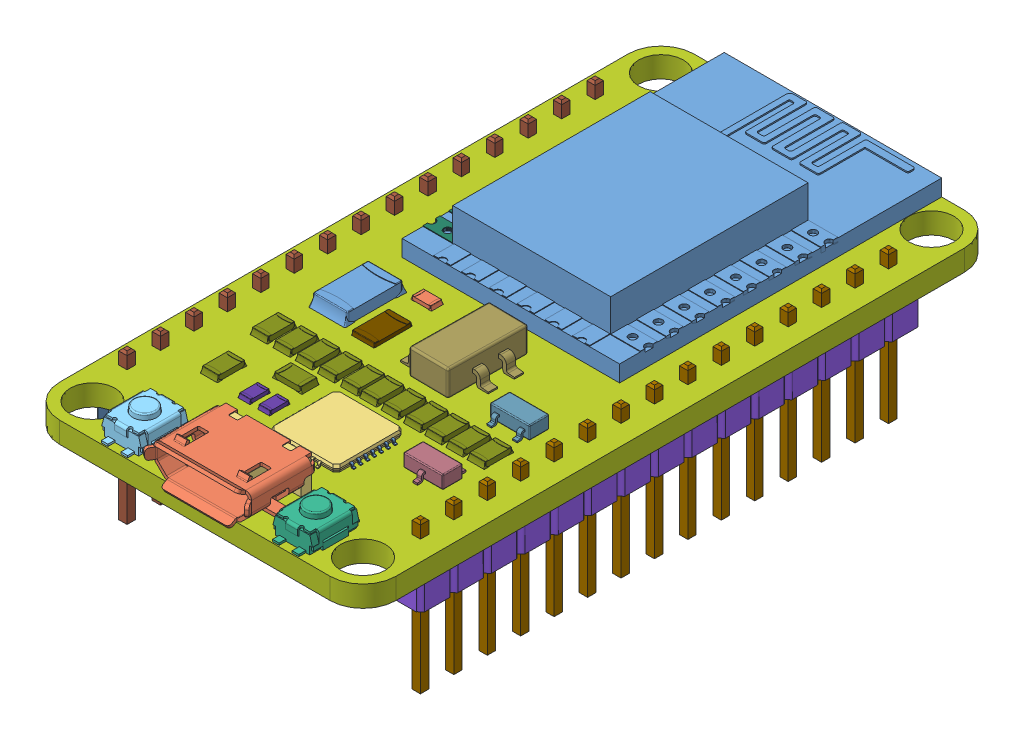
SolidWorks assembly ESP8266 v7, configuration Default. Lengths in mm.
Overall size (25.55 14.09 48.82).
128 component instances, 21 part files, 0 mates.
Components (placement in the parent):
- ESP8266 v7-1: ESP8266 v7 [Default] at origin size (16.52 3.75 40.51)
- micro usb v1-1: micro usb v1 [Default] at (12.6689 12.0548 1.95) x (0 -1 0) z (-1 0 0) size (3.25 6.18 8.01)
  - micro usb shell-1: micro usb shell [Default] at (10.11 -1.95 -0.7124) x (0 0 -1) z (0 1 0) size (8.01 2.95 5.63)
  - micro usb internal-1: micro usb internal [Default] at (10.36 -1.95 -0.7124) x (0 0 -1) z (0 1 0) size (6.9 2.9 4)
  - micro usb contact-1: micro usb contact [Default] at (10.36 -2.05 -2.0124) x (0 0 -1) z (0 1 0) size (0.2 1.3 4.65)
  - micro usb contact-2: micro usb contact [Default] at (10.36 -2.05 -1.3624) x (0 0 -1) z (0 1 0) size (0.2 1.3 4.65)
  - micro usb contact-3: micro usb contact [Default] at (10.36 -2.05 -0.7124) x (0 0 -1) z (0 1 0) size (0.2 1.3 4.65)
  - micro usb contact-4: micro usb contact [Default] at (10.36 -2.05 -0.0624) x (0 0 -1) z (0 1 0) size (0.2 1.3 4.65)
  - micro usb contact-5: micro usb contact [Default] at (10.36 -2.05 0.5876) x (0 0 -1) z (0 1 0) size (0.2 1.3 4.65)
- switch v1-1: switch v1 [Default] at (-4.6798 0 12.1544) x (1 0 0) z (0 1 0) size (3 4.6 1.85)
- switch v1 (1)-1: switch v1 (1) [Default] at (8.3273 0 12.1544) x (1 0 0) z (0 1 0) size (3 4.6 1.85)
- Placa Base-1: Placa Base [Default] at origin size (25.55 11.43 48.19)
  - Placa Base-1: Placa Base [Default] at origin size (25.55 1.6 48.19)
  - Pin Header 1x15 TH Pitch 2.54mm v3 v1-1: Pin Header 1x15 TH Pitch 2.54mm v3 v1 [Default] at (24.996 0.1484 -10.5049) x (0 0 -1) z (0 1 0) size (38.1 2.59 11.43)
    - asm_pin-1: asm_pin [Default] at (-4.318 1.27 0.0014) x (1 0 0) z (0 0 -1) size (2.54 2.59 11.43)
      - spacer-1: spacer [Default] at origin size (2.54 2.59 2.54)
      - pin-1: pin [Default] at origin size (0.64 0.64 11.43)
    - asm_pin_1-1: asm_pin_1 [Default] at (-1.778 1.27 0.0014) x (1 0 0) z (0 0 -1) size (2.54 2.59 11.43)
      - spacer-1: spacer [Default] at origin size (2.54 2.59 2.54)
      - pin-1: pin [Default] at origin size (0.64 0.64 11.43)
    - asm_pin_2-1: asm_pin_2 [Default] at (0.762 1.27 0.0014) x (1 0 0) z (0 0 -1) size (2.54 2.59 11.43)
      - spacer-1: spacer [Default] at origin size (2.54 2.59 2.54)
      - pin-1: pin [Default] at origin size (0.64 0.64 11.43)
    - asm_pin_3-1: asm_pin_3 [Default] at (3.302 1.27 0.0014) x (1 0 0) z (0 0 -1) size (2.54 2.59 11.43)
      - spacer-1: spacer [Default] at origin size (2.54 2.59 2.54)
      - pin-1: pin [Default] at origin size (0.64 0.64 11.43)
    - asm_pin_4-1: asm_pin_4 [Default] at (5.842 1.27 0.0014) x (1 0 0) z (0 0 -1) size (2.54 2.59 11.43)
      - spacer-1: spacer [Default] at origin size (2.54 2.59 2.54)
      - pin-1: pin [Default] at origin size (0.64 0.64 11.43)
    - asm_pin_5-1: asm_pin_5 [Default] at (8.382 1.27 0.0014) x (1 0 0) z (0 0 -1) size (2.54 2.59 11.43)
      - spacer-1: spacer [Default] at origin size (2.54 2.59 2.54)
      - pin-1: pin [Default] at origin size (0.64 0.64 11.43)
    - asm_pin_6-1: asm_pin_6 [Default] at (10.922 1.27 0.0014) x (1 0 0) z (0 0 -1) size (2.54 2.59 11.43)
      - spacer-1: spacer [Default] at origin size (2.54 2.59 2.54)
      - pin-1: pin [Default] at origin size (0.64 0.64 11.43)
    - asm_pin_7-1: asm_pin_7 [Default] at (13.462 1.27 0.0014) x (1 0 0) z (0 0 -1) size (2.54 2.59 11.43)
      - spacer-1: spacer [Default] at origin size (2.54 2.59 2.54)
      - pin-1: pin [Default] at origin size (0.64 0.64 11.43)
    - asm_pin_8-1: asm_pin_8 [Default] at (16.002 1.27 0.0014) x (1 0 0) z (0 0 -1) size (2.54 2.59 11.43)
      - spacer-1: spacer [Default] at origin size (2.54 2.59 2.54)
      - pin-1: pin [Default] at origin size (0.64 0.64 11.43)
    - asm_pin_9-1: asm_pin_9 [Default] at (18.542 1.27 0.0014) x (1 0 0) z (0 0 -1) size (2.54 2.59 11.43)
      - spacer-1: spacer [Default] at origin size (2.54 2.59 2.54)
      - pin-1: pin [Default] at origin size (0.64 0.64 11.43)
    - asm_pin_10-1: asm_pin_10 [Default] at (21.082 1.27 0.0014) x (1 0 0) z (0 0 -1) size (2.54 2.59 11.43)
      - spacer-1: spacer [Default] at origin size (2.54 2.59 2.54)
      - pin-1: pin [Default] at origin size (0.64 0.64 11.43)
    - asm_pin_11-1: asm_pin_11 [Default] at (23.622 1.27 0.0014) x (1 0 0) z (0 0 -1) size (2.54 2.59 11.43)
      - spacer-1: spacer [Default] at origin size (2.54 2.59 2.54)
      - pin-1: pin [Default] at origin size (0.64 0.64 11.43)
    - asm_pin_12-1: asm_pin_12 [Default] at (26.1619 1.27 0.0014) x (1 0 0) z (0 0 -1) size (2.54 2.59 11.43)
      - spacer-1: spacer [Default] at origin size (2.54 2.59 2.54)
      - pin-1: pin [Default] at origin size (0.64 0.64 11.43)
    - asm_pin_13-1: asm_pin_13 [Default] at (28.702 1.27 0.0014) x (1 0 0) z (0 0 -1) size (2.54 2.59 11.43)
      - spacer-1: spacer [Default] at origin size (2.54 2.59 2.54)
      - pin-1: pin [Default] at origin size (0.64 0.64 11.43)
    - asm_pin_14-1: asm_pin_14 [Default] at (31.242 1.27 0.0014) x (1 0 0) z (0 0 -1) size (2.54 2.59 11.43)
      - spacer-1: spacer [Default] at origin size (2.54 2.59 2.54)
      - pin-1: pin [Default] at origin size (0.64 0.64 11.43)
  - Pin Header 1x15 TH Pitch 2.54mm v3 v1 (1) (1)-1: Pin Header 1x15 TH Pitch 2.54mm v3 v1 (1) (1) [Default] at (2.7074 0.1484 -10.5049) x (0 0 -1) z (0 1 0) size (38.1 2.59 11.43)
    - asm_pin (1) (1)-1: asm_pin (1) (1) [Default] at (-4.318 1.27 0.0014) x (1 0 0) z (0 0 -1) size (2.54 2.59 11.43)
      - spacer (1) (1)-1: spacer (1) (1) [Default] at origin size (2.54 2.59 2.54)
      - pin (1) (1)-1: pin (1) (1) [Default] at origin size (0.64 0.64 11.43)
    - asm_pin (1) (1)_1-1: asm_pin (1) (1)_1 [Default] at (-1.778 1.27 0.0014) x (1 0 0) z (0 0 -1) size (2.54 2.59 11.43)
      - spacer (1) (1)-1: spacer (1) (1) [Default] at origin size (2.54 2.59 2.54)
      - pin (1) (1)-1: pin (1) (1) [Default] at origin size (0.64 0.64 11.43)
    - asm_pin (1) (1)_2-1: asm_pin (1) (1)_2 [Default] at (0.762 1.27 0.0014) x (1 0 0) z (0 0 -1) size (2.54 2.59 11.43)
      - spacer (1) (1)-1: spacer (1) (1) [Default] at origin size (2.54 2.59 2.54)
      - pin (1) (1)-1: pin (1) (1) [Default] at origin size (0.64 0.64 11.43)
    - asm_pin (1) (1)_3-1: asm_pin (1) (1)_3 [Default] at (3.302 1.27 0.0014) x (1 0 0) z (0 0 -1) size (2.54 2.59 11.43)
      - spacer (1) (1)-1: spacer (1) (1) [Default] at origin size (2.54 2.59 2.54)
      - pin (1) (1)-1: pin (1) (1) [Default] at origin size (0.64 0.64 11.43)
    - asm_pin (1) (1)_4-1: asm_pin (1) (1)_4 [Default] at (5.842 1.27 0.0014) x (1 0 0) z (0 0 -1) size (2.54 2.59 11.43)
      - spacer (1) (1)-1: spacer (1) (1) [Default] at origin size (2.54 2.59 2.54)
      - pin (1) (1)-1: pin (1) (1) [Default] at origin size (0.64 0.64 11.43)
    - asm_pin (1) (1)_5-1: asm_pin (1) (1)_5 [Default] at (8.382 1.27 0.0014) x (1 0 0) z (0 0 -1) size (2.54 2.59 11.43)
      - spacer (1) (1)-1: spacer (1) (1) [Default] at origin size (2.54 2.59 2.54)
      - pin (1) (1)-1: pin (1) (1) [Default] at origin size (0.64 0.64 11.43)
    - asm_pin (1) (1)_6-1: asm_pin (1) (1)_6 [Default] at (10.922 1.27 0.0014) x (1 0 0) z (0 0 -1) size (2.54 2.59 11.43)
      - spacer (1) (1)-1: spacer (1) (1) [Default] at origin size (2.54 2.59 2.54)
      - pin (1) (1)-1: pin (1) (1) [Default] at origin size (0.64 0.64 11.43)
    - asm_pin (1) (1)_7-1: asm_pin (1) (1)_7 [Default] at (13.462 1.27 0.0014) x (1 0 0) z (0 0 -1) size (2.54 2.59 11.43)
      - spacer (1) (1)-1: spacer (1) (1) [Default] at origin size (2.54 2.59 2.54)
      - pin (1) (1)-1: pin (1) (1) [Default] at origin size (0.64 0.64 11.43)
    - asm_pin (1) (1)_8-1: asm_pin (1) (1)_8 [Default] at (16.002 1.27 0.0014) x (1 0 0) z (0 0 -1) size (2.54 2.59 11.43)
      - spacer (1) (1)-1: spacer (1) (1) [Default] at origin size (2.54 2.59 2.54)
      - pin (1) (1)-1: pin (1) (1) [Default] at origin size (0.64 0.64 11.43)
    - asm_pin (1) (1)_9-1: asm_pin (1) (1)_9 [Default] at (18.542 1.27 0.0014) x (1 0 0) z (0 0 -1) size (2.54 2.59 11.43)
      - spacer (1) (1)-1: spacer (1) (1) [Default] at origin size (2.54 2.59 2.54)
      - pin (1) (1)-1: pin (1) (1) [Default] at origin size (0.64 0.64 11.43)
    - asm_pin (1) (1)_10-1: asm_pin (1) (1)_10 [Default] at (21.082 1.27 0.0014) x (1 0 0) z (0 0 -1) size (2.54 2.59 11.43)
      - spacer (1) (1)-1: spacer (1) (1) [Default] at origin size (2.54 2.59 2.54)
      - pin (1) (1)-1: pin (1) (1) [Default] at origin size (0.64 0.64 11.43)
    - asm_pin (1) (1)_11-1: asm_pin (1) (1)_11 [Default] at (23.622 1.27 0.0014) x (1 0 0) z (0 0 -1) size (2.54 2.59 11.43)
      - spacer (1) (1)-1: spacer (1) (1) [Default] at origin size (2.54 2.59 2.54)
      - pin (1) (1)-1: pin (1) (1) [Default] at origin size (0.64 0.64 11.43)
    - asm_pin (1) (1)_12-1: asm_pin (1) (1)_12 [Default] at (26.1619 1.27 0.0014) x (1 0 0) z (0 0 -1) size (2.54 2.59 11.43)
      - spacer (1) (1)-1: spacer (1) (1) [Default] at origin size (2.54 2.59 2.54)
      - pin (1) (1)-1: pin (1) (1) [Default] at origin size (0.64 0.64 11.43)
    - asm_pin (1) (1)_13-1: asm_pin (1) (1)_13 [Default] at (28.702 1.27 0.0014) x (1 0 0) z (0 0 -1) size (2.54 2.59 11.43)
      - spacer (1) (1)-1: spacer (1) (1) [Default] at origin size (2.54 2.59 2.54)
      - pin (1) (1)-1: pin (1) (1) [Default] at origin size (0.64 0.64 11.43)
    - asm_pin (1) (1)_14-1: asm_pin (1) (1)_14 [Default] at (31.242 1.27 0.0014) x (1 0 0) z (0 0 -1) size (2.54 2.59 11.43)
      - spacer (1) (1)-1: spacer (1) (1) [Default] at origin size (2.54 2.59 2.54)
      - pin (1) (1)-1: pin (1) (1) [Default] at origin size (0.64 0.64 11.43)
- TSOP-5 v4 v1-1: TSOP-5 v4 v1 [Default] at (-0.2513 -0.1563 0.1159) x (-0.013485 0 0.999909) z (0 1 0) size (6.03 5.43 2.12)
- TSOP-5 v4 v1 (1)-1: TSOP-5 v4 v1 (1) [Default] at (20.2211 1.5986 -10.6444) x (1 0 0) z (0 1 0) size (3.02 2.71 1.06)
- TSOP-5 v4 v1 (1) (1)-1: TSOP-5 v4 v1 (1) (1) [Default] at (20.2211 1.5625 -17.2293) x (-1 0 0) z (0 1 0) size (3.02 2.71 1.06)
- Component41-1: Component41 [Default] at origin size (2.26 1.3 15)
- R0805-NO v1-1: R0805-NO v1 [Default] at (8.8909 1.5658 -11.5498) x (1 0 0) z (0 1 0) size (2.33 1.37 0.46)
- R0805-NO v1-2: R0805-NO v1 [Default] at (5.3832 1.5658 -9.5734) x (0 0 1) z (0 1 0) size (2.33 1.37 0.46)
- R0805-NO v1-3: R0805-NO v1 [Default] at (4.7384 1.5658 -14.0063) x (0 0 1) z (0 1 0) size (2.33 1.37 0.46)
- R0805-NO v1-4: R0805-NO v1 [Default] at (21.2208 1.5658 -14.0063) x (0 0 1) z (0 1 0) size (2.33 1.37 0.46)
- R0805-NO v1-5: R0805-NO v1 [Default] at (19.6088 1.5658 -14.0063) x (0 0 1) z (0 1 0) size (2.33 1.37 0.46)
- R0805-NO v1-6: R0805-NO v1 [Default] at (17.9968 1.5658 -14.0063) x (0 0 1) z (0 1 0) size (2.33 1.37 0.46)
- R0805-NO v1-7: R0805-NO v1 [Default] at (16.3849 1.5658 -14.0063) x (0 0 1) z (0 1 0) size (2.33 1.37 0.46)
- R0805-NO v1-8: R0805-NO v1 [Default] at (14.6923 1.5658 -14.0063) x (0 0 1) z (0 1 0) size (2.33 1.37 0.46)
- R0805-NO v1-9: R0805-NO v1 [Default] at (13.04 1.5658 -14.0063) x (0 0 1) z (0 1 0) size (2.33 1.37 0.46)
- R0805-NO v1-10: R0805-NO v1 [Default] at (11.5893 1.5658 -14.0063) x (0 0 1) z (0 1 0) size (2.33 1.37 0.46)
- R0805-NO v1-11: R0805-NO v1 [Default] at (9.8564 1.5658 -14.0063) x (0 0 1) z (0 1 0) size (2.33 1.37 0.46)
- R0805-NO v1-12: R0805-NO v1 [Default] at (8.1638 1.5658 -14.0063) x (0 0 1) z (0 1 0) size (2.33 1.37 0.46)
- R0805-NO v1-13: R0805-NO v1 [Default] at (6.4713 1.5658 -14.0063) x (0 0 1) z (0 1 0) size (2.33 1.37 0.46)
- R0805-NO v1 (1)-1: R0805-NO v1 (1) [Default] at (8.4415 1.5658 -9.3168) x (0 0 1) z (0 1 0) size (1.63 0.96 0.32)
- R0805-NO v1 (1)-2: R0805-NO v1 (1) [Default] at (9.9358 1.5658 -9.3168) x (0 0 1) z (0 1 0) size (1.63 0.96 0.32)
- R0805-NO v1 (1) (1)-1: R0805-NO v1 (1) (1) [Default] at (8.597 1.5658 -17.758) x (0 0 1) z (0 1 0) size (3.26 1.92 0.63)
- R0805-NO v1 (1) (2)-1: R0805-NO v1 (1) (2) [Default] at (4.6179 1.5658 -48.9696) x (0 0 1) z (0 1 0) size (4.89 2.88 0.95)
- R0805-NO v1 (1) (3)-1: R0805-NO v1 (1) (3) [Default] at (8.3907 1.5658 -21.9299) x (1 0 0) z (0 1 0) size (1.63 0.96 0.32)
- Cuerpo Microprocesador v1-1: Cuerpo Microprocesador v1 [Default] at (13.4174 0.8784 -8.5282) size (5.17 0.51 5.78)
